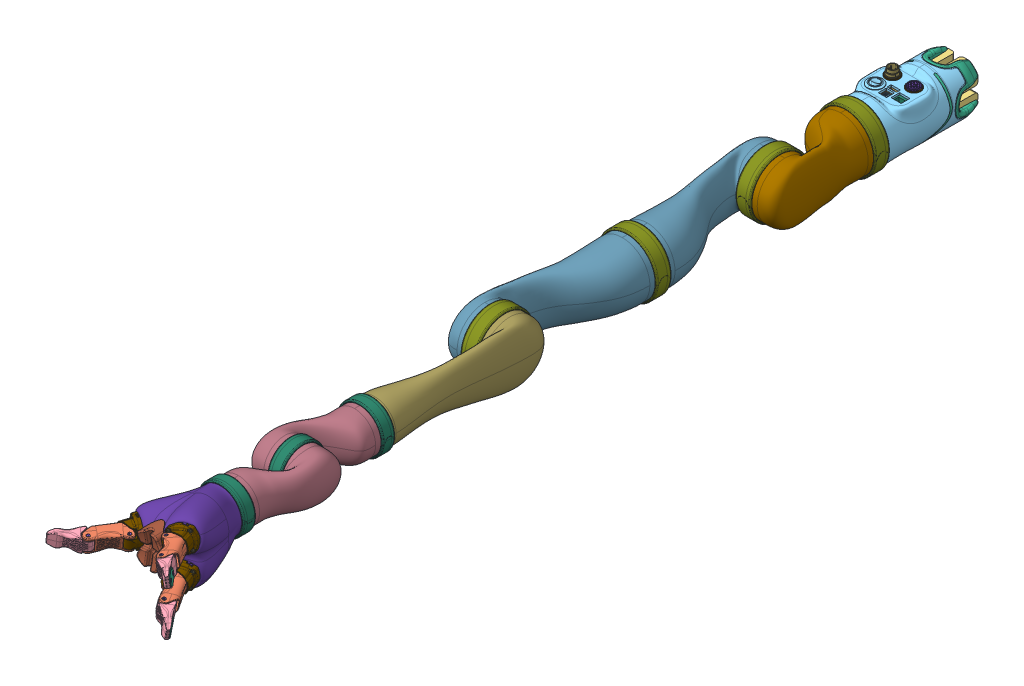
SolidWorks assembly JACO 7 DOF S + KG-3_revA.STEP, configuration 默认. Lengths in mm.
Overall size (206.48 115.63 1296.6).
225 component instances, 48 part files, 0 mates.
Components (placement in the parent):
- AP 4075 0003.STEP-1: AP 4075 0003.STEP [默认] at origin size (107.79 107.79 156.6)
  - AM 4075 0005.STEP-1: AM 4075 0005.STEP [默认] at origin size (107.79 107.79 156.6)
    - AM 4075 0004.STEP-1: AM 4075 0004.STEP [默认] at origin size (107.79 107.79 156.6)
      - AM 7525 0001.STEP-1: AM 7525 0001.STEP [默认] at (0 0 156.5) x (0 0 -1) z (0.382683 0.92388 0) size (25.6 82.5 82.5)
        - MR 7580 0001.STEP-1: MR 7580 0001.STEP [默认] at origin size (25.6 82.5 82.5)
        - MH 0304 0001.STEP-1: MH 0304 0001.STEP [默认] at (15 19.7505 29.5587) x (1 0 0) z (0 0.55557 0.83147) size (3 3 3.98)
      - MF 7549 0001_D_faut.STEP-1: MF 7549 0001_D_faut.STEP [默认] x (0 -1 0) z (-1 0 0) size (74.66 49 74.66)
      - MP 8010 0001_D_faut.STEP-1: MP 8010 0001_D_faut.STEP [默认] at (0 0 54) x (1 0 0) z (0 -1 0) size (77.22 9.56 77.22)
      - MT 8080 0008_D_faut.STEP-1: MT 8080 0008_D_faut.STEP [默认] at (0 0 58) x (0 -1 0) z (1 0 0) size (87.16 131.35 84.58)
    - DL 2311 0001_D_faut.STEP-1: DL 2311 0001_D_faut.STEP [默认] at (0 0 59.5) x (0 1 0) z (1 0 0) size (79.71 59.58 82.7)
  - AE 0000 0022_D_faut.STEP-1: AE 0000 0022_D_faut.STEP [默认] at (0.6864 -1.7716 54.8) x (0 -1 0) z (0 0 1) size (53.01 55.6 17.26)
    - PCB_Backplane_D_faut.STEP-1: PCB_Backplane_D_faut.STEP [默认] at (0.6913 -0.6913 -0.8) size (53.01 55.6 1.6)
    - HSEC8-125-01-X-DV-A_D_faut.STEP-1: HSEC8-125-01-X-DV-A_D_faut.STEP [默认] at (-5 0 0.8) x (0 -1 0) z (-1 0 0) size (27.8 9.3 7)
    - HSEC8-125-01-X-DV-A_D_faut.STEP-2: HSEC8-125-01-X-DV-A_D_faut.STEP [默认] at (5 0 0.8) x (0 -1 0) z (-1 0 0) size (27.8 9.3 7)
    - HSEC8-125-01-X-DV-A_D_faut.STEP-3: HSEC8-125-01-X-DV-A_D_faut.STEP [默认] at (15 0 0.8) x (0 -1 0) z (-1 0 0) size (27.8 9.3 7)
    - HSEC8-125-01-X-DV-A_D_faut.STEP-4: HSEC8-125-01-X-DV-A_D_faut.STEP [默认] at (-15 0 0.8) x (0 -1 0) z (-1 0 0) size (27.8 9.3 7)
    - Cap_Backplane_D_faut.STEP-1: Cap_Backplane_D_faut.STEP [默认] at (-29.1669 5.7481 0.8) x (1 0 0) z (0 -1 0) size (10 10.5 10)
    - Cap_Backplane_D_faut.STEP-2: Cap_Backplane_D_faut.STEP [默认] at (-29.1669 -5.4094 0.8) x (1 0 0) z (0 -1 0) size (10 10.5 10)
    - Cap_Backplane_D_faut.STEP-3: Cap_Backplane_D_faut.STEP [默认] at (-29.1669 -16.1366 0.8) x (1 0 0) z (0 -1 0) size (10 10.5 10)
    - Samtec-SIB-108-02-F-S_LEAD STYLE2PLATINGFPOSITIONS8ROWS.STEP-1: Samtec-SIB-108-02-F-S_LEAD STYLE2PLATINGFPOSITIONS8ROWS.STEP [默认] at (-4.2479 -0.6913 -0.8) x (0 -1 0) z (1 0 0) size (20.32 5.23 8.51)
    - Samtec-SIB-108-02-F-S_LEAD STYLE2PLATINGFPOSITIONS8ROWS.STEP-2: Samtec-SIB-108-02-F-S_LEAD STYLE2PLATINGFPOSITIONS8ROWS.STEP [默认] at (5.7521 -0.6913 -0.8) x (0 -1 0) z (1 0 0) size (20.32 5.23 8.51)
  - AE 0000 0021_D_faut.STEP-1: AE 0000 0021_D_faut.STEP [默认] at (-8.7893 14.275 82.5565) x (-1 0 0) z (0 -1 0) size (65 62 35.39)
    - EDAC-690-004-260-013_Default USB - Type A004-4 Contacts2-Gold Flash60-Vertical PCB0-Thermoplastic Black or Blue.STEP-1: EDAC-690-004-260-013_Default USB - Type A004-4 Contacts2-Gold Flash60-Vertical PCB0-Thermoplastic Black or Blue.STEP [默认] at (-10.8593 -15.6435 -15.675) x (-1 0 0) z (0 0 -1) size (15.84 7 18.8)
      - EDAC-690-004-260-013_690-004_690-004-260-013.STEP-1: EDAC-690-004-260-013_690-004_690-004-260-013.STEP [默认] at origin size (15.84 7 18.8)
        - EDAC-690-004-260-013_690-004_690-004-260-013-0.STEP-1: EDAC-690-004-260-013_690-004_690-004-260-013-0.STEP [默认] at origin size (15.84 7 18.8)
    - Lumberg_0315_04_D_faut.STEP-1: Lumberg_0315_04_D_faut.STEP [默认] at (7.2107 0.5565 -31.805) x (0 0 1) z (1 0 0) size (18 20 20)
      - 0315_04_D_faut.STEP-1: 0315_04_D_faut.STEP [默认] at (24.0344 -13.1103 0) x (0 1 0) z (0 0 1) size (20 18 20)
    - PCB_Mezzanine_2_D_faut.STEP-1: PCB_Mezzanine_2_D_faut.STEP [默认] at (-41.4793 -37.2935 0) size (65 62 1.55)
    - c-5787834-1-a-3d_D_faut.STEP-1: c-5787834-1-a-3d_D_faut.STEP [默认] at (-10.8263 -26.7115 -16.075) x (1 0 0) z (0 0 -1) size (15.15 11.46 19.64)
    - SI-46001-F_D_faut.STEP-1: SI-46001-F_D_faut.STEP [默认] at (-19.9593 -12.9235 -17.795) x (-1 0 0) z (0 1 0) size (16.26 17.02 17.02)
    - Main_Switch_D_faut.STEP-1: Main_Switch_D_faut.STEP [默认] at (9.0907 -23.4405 -4.815) x (0 1 0) z (0 0 1) size (23 23 28.61)
    - 0305_08-1_D_faut.STEP-1: 0305_08-1_D_faut.STEP [默认] at (-12.2893 0.5565 -31.705) x (-1 0 0) z (0 0 -1) size (20 20 18.1)
    - Lumberg_Screw_D_faut.STEP-1: Lumberg_Screw_D_faut.STEP [默认] at (-24.7893 0.5565 -22.305) x (0.150539 0.988604 0) z (0 0 1) size (20 20 3)
    - Lumberg_Screw_D_faut.STEP-2: Lumberg_Screw_D_faut.STEP [默认] at (7.2107 0.5565 -22.305) x (0.972925 0.231122 0) z (0 0 1) size (20 20 3)
  - MF 7482 0001_D_faut.STEP-1: MF 7482 0001_D_faut.STEP [默认] at (0 0 119.85) x (0 1 0) z (0 0 -1) size (50.6 74.1 81.85)
  - MH 0306 0003_96817A310.STEP-1: MH 0306 0003_96817A310.STEP [默认] at (20 -11.42 55.6) x (0.976803 -0.214141 0) z (0 0 1) size (5 5 8.1)
  - MH 0306 0003_96817A310.STEP-2: MH 0306 0003_96817A310.STEP [默认] at (-17 -24.5 56.5) x (-0.999847 0.017484 0) z (0 0 1) size (5 5 8.1)
  - MH 0306 0003_96817A310.STEP-3: MH 0306 0003_96817A310.STEP [默认] at (17 -24.5 56.5) x (0.590726 0.806872 0) z (0 0 1) size (5 5 8.1)
  - MH 0306 0003_96817A310.STEP-4: MH 0306 0003_96817A310.STEP [默认] at (-20 -11.42 55.6) x (0.99968 -0.025284 0) z (0 0 1) size (5 5 8.1)
  - MF 1064 0002_D_faut.STEP-1: MF 1064 0002_D_faut.STEP [默认] at (-0.0013 32 108.003) x (-1 0 0) z (0 -1 0) size (64 31 8.22)
  - MF 1064 0002_D_faut.STEP-2: MF 1064 0002_D_faut.STEP [默认] at (-0.0013 23.775 108.003) x (-1 0 0) z (0 -1 0) size (64 31 8.22)
  - MP 6856 0001_D_faut.STEP-1: MP 6856 0001_D_faut.STEP [默认] at (33.94 -0.2666 113.85) x (-1 0 0) z (0 0 1) size (67.5 5.5 56)
  - CS 0000 0003_D_faut.STEP-1: CS 0000 0003_D_faut.STEP [默认] at (-17.88 20.5 106) x (0.009293 0 -0.999957) z (0 -1 0) size (23 23 28.61)
  - MI 8660 0001_D_faut.STEP-1: MI 8660 0001_D_faut.STEP [默认] x (0 -1 0) z (-1 0 0) size (82.51 46.49 82.53)
  - AE 0000 0023_D_faut.STEP-1: AE 0000 0023_D_faut.STEP [默认] at (32.69 3.0084 116.85) x (-1 0 0) z (0 -1 0) size (65 59 1.55)
  - MH 0305 0003_92005A114.STEP-1: MH 0305 0003_92005A114.STEP [默认] at (-28.31 -1.2166 68.19) x (1 0 0) z (0 1 0) size (6 6 7.42)
  - MH 0305 0003_92005A114.STEP-2: MH 0305 0003_92005A114.STEP [默认] at (28.69 -1.2166 68.19) x (1 0 0) z (0 1 0) size (6 6 7.42)
- AM 7575 0005.STEP-1: AM 7575 0005.STEP [默认] at (0 0 157) x (0 0 1) z (-1 0 0) size (172.49 107.79 107.79)
  - AM 7575 0002_D_faut.STEP-1: AM 7575 0002_D_faut.STEP [默认] at origin size (172.49 107.79 107.79)
    - AM 7525 0001.STEP-1: AM 7525 0001.STEP [默认] x (1 0 0) z (0 -0.382683 0.92388) size (25.6 82.5 82.5)
      - MR 7580 0001.STEP-1: MR 7580 0001.STEP [默认] at origin size (25.6 82.5 82.5)
      - MH 0304 0001.STEP-1: MH 0304 0001.STEP [默认] at (15 19.7505 29.5587) x (1 0 0) z (0 0.55557 0.83147) size (3 3 3.98)
    - AM 7525 0001.STEP-2: AM 7525 0001.STEP [默认] at (118.5 0 1.5) x (0 0 -1) z (0.92388 -0.382683 0) size (25.6 82.5 82.5)
      - MR 7580 0001.STEP-1: MR 7580 0001.STEP [默认] at origin size (25.6 82.5 82.5)
      - MH 0304 0001.STEP-1: MH 0304 0001.STEP [默认] at (15 19.7505 29.5587) x (1 0 0) z (0 0.55557 0.83147) size (3 3 3.98)
    - MT 8080 0001_D_faut.STEP-1: MT 8080 0001_D_faut.STEP [默认] at (118.5 0 -7) x (-1 0 0) z (0 1 0) size (151.26 82.78 82.54)
- AM 7558 0003.STEP-1: AM 7558 0003.STEP [默认] at (-1.5 0 685.5) x (1 0 0) z (0 0 -1) size (63.12 107.79 260.9)
  - AM 7558 0001_D_faut.STEP-1: AM 7558 0001_D_faut.STEP [默认] at origin size (63.12 107.79 260.9)
    - AM 7525 0001.STEP-1: AM 7525 0001.STEP [默认] x (1 0 0) z (0 -0.382683 0.92388) size (25.6 82.5 82.5)
      - MR 7580 0001.STEP-1: MR 7580 0001.STEP [默认] at origin size (25.6 82.5 82.5)
      - MH 0304 0001.STEP-1: MH 0304 0001.STEP [默认] at (15 19.7505 29.5587) x (1 0 0) z (0 0.55557 0.83147) size (3 3 3.98)
    - AM 5818 0003.STEP-1: AM 5818 0003.STEP [默认] at (11.25 0 -207) x (0 0 1) z (1 0 0) size (18 63 63)
      - MR 5862 0001.STEP-1: MR 5862 0001.STEP [默认] at origin size (18 63 63)
      - MH 0303 0003_D_faut.STEP-1: MH 0303 0003_D_faut.STEP [默认] at (11 -14.9 -25.8076) x (0 0.5 0.866025) z (-0.866025 -0.433013 0.25) size (2.5 3 3)
    - MT 8062 0001_D_faut.STEP-1: MT 8062 0001_D_faut.STEP [默认] at (8.5 0 0) x (0 0 -1) z (-1 0 0) size (241.26 82.53 63.12)
- KR823.STEP-1: KR823.STEP [默认] at (9.75 0 900) x (0 0 1) z (0 1 0) size (135.27 79.25 63.1)
  - AM 5858 0008.STEP-1: AM 5858 0008.STEP [默认] at origin size (135.27 79.25 63.1)
    - AM 5818 0003.STEP-1: AM 5818 0003.STEP [默认] at (-7 0 0) x (1 0 0) z (0 -1 0) size (18 63 63)
      - MR 5862 0001.STEP-1: MR 5862 0001.STEP [默认] at origin size (18 63 63)
      - MH 0303 0003_D_faut.STEP-1: MH 0303 0003_D_faut.STEP [默认] at (11 -14.9 -25.8076) x (0 0.5 0.866025) z (-0.866025 -0.433013 0.25) size (2.5 3 3)
    - AM 5818 0003.STEP-2: AM 5818 0003.STEP [默认] at (96.5 -0.25 0) x (0 -1 0) z (-1 0 0) size (18 63 63)
      - MR 5862 0001.STEP-1: MR 5862 0001.STEP [默认] at origin size (18 63 63)
      - MH 0303 0003_D_faut.STEP-1: MH 0303 0003_D_faut.STEP [默认] at (11 -14.9 -25.8076) x (0 0.5 0.866025) z (-0.866025 -0.433013 0.25) size (2.5 3 3)
    - MT 6262 0006.STEP-1: MT 6262 0006.STEP [默认] x (-1 0 0) z (0 0 1) size (128.27 79.25 63.1)
- KR823.STEP-2: KR823.STEP [默认] at (9.75 0 1093) x (0 0 -1) z (0 1 0) size (135.27 79.25 63.1)
  - AM 5858 0008.STEP-1: AM 5858 0008.STEP [默认] at origin size (135.27 79.25 63.1)
    - AM 5818 0003.STEP-1: AM 5818 0003.STEP [默认] at (-7 0 0) x (1 0 0) z (0 -1 0) size (18 63 63)
      - MR 5862 0001.STEP-1: MR 5862 0001.STEP [默认] at origin size (18 63 63)
      - MH 0303 0003_D_faut.STEP-1: MH 0303 0003_D_faut.STEP [默认] at (11 -14.9 -25.8076) x (0 0.5 0.866025) z (-0.866025 -0.433013 0.25) size (2.5 3 3)
    - AM 5818 0003.STEP-2: AM 5818 0003.STEP [默认] at (96.5 -0.25 0) x (0 -1 0) z (-1 0 0) size (18 63 63)
      - MR 5862 0001.STEP-1: MR 5862 0001.STEP [默认] at origin size (18 63 63)
      - MH 0303 0003_D_faut.STEP-1: MH 0303 0003_D_faut.STEP [默认] at (11 -14.9 -25.8076) x (0 0.5 0.866025) z (-0.866025 -0.433013 0.25) size (2.5 3 3)
    - MT 6262 0006.STEP-1: MT 6262 0006.STEP [默认] x (-1 0 0) z (0 0 1) size (128.27 79.25 63.1)
- KR822.STEP-1: KR822.STEP [默认] at (-10.5 0 275.5) x (0 0 1) z (0 1 0) size (258.74 107.79 107.79)
  - AM 7575 0010.STEP-1: AM 7575 0010.STEP [默认] at origin size (258.74 107.79 107.79)
    - AM 7525 0001.STEP-1: AM 7525 0001.STEP [默认] at (0 8.5 0) x (0 -1 0) z (-0.92388 0 -0.382683) size (25.6 82.5 82.5)
      - MR 7580 0001.STEP-1: MR 7580 0001.STEP [默认] at origin size (25.6 82.5 82.5)
      - MH 0304 0001.STEP-1: MH 0304 0001.STEP [默认] at (15 19.7505 29.5587) x (1 0 0) z (0 0.55557 0.83147) size (3 3 3.98)
    - AM 7525 0001.STEP-2: AM 7525 0001.STEP [默认] at (204.75 8.75 0) x (-1 0 0) z (0 0.92388 -0.382683) size (25.6 82.5 82.5)
      - MR 7580 0001.STEP-1: MR 7580 0001.STEP [默认] at origin size (25.6 82.5 82.5)
      - MH 0304 0001.STEP-1: MH 0304 0001.STEP [默认] at (15 19.7505 29.5587) x (1 0 0) z (0 0.55557 0.83147) size (3 3 3.98)
    - MT 8080 0009_D_faut.STEP-1: MT 8080 0009_D_faut.STEP [默认] at origin size (237.61 85.04 82.69)
- KR822.STEP-2: KR822.STEP [默认] at (-10.5 0 685.5) x (0 0 -1) z (0 -1 0) size (258.74 107.79 107.79)
  - AM 7575 0010.STEP-1: AM 7575 0010.STEP [默认] at origin size (258.74 107.79 107.79)
    - AM 7525 0001.STEP-1: AM 7525 0001.STEP [默认] at (0 8.5 0) x (0 -1 0) z (-0.92388 0 -0.382683) size (25.6 82.5 82.5)
      - MR 7580 0001.STEP-1: MR 7580 0001.STEP [默认] at origin size (25.6 82.5 82.5)
      - MH 0304 0001.STEP-1: MH 0304 0001.STEP [默认] at (15 19.7505 29.5587) x (1 0 0) z (0 0.55557 0.83147) size (3 3 3.98)
    - AM 7525 0001.STEP-2: AM 7525 0001.STEP [默认] at (204.75 8.75 0) x (-1 0 0) z (0 0.92388 -0.382683) size (25.6 82.5 82.5)
      - MR 7580 0001.STEP-1: MR 7580 0001.STEP [默认] at origin size (25.6 82.5 82.5)
      - MH 0304 0001.STEP-1: MH 0304 0001.STEP [默认] at (15 19.7505 29.5587) x (1 0 0) z (0 0.55557 0.83147) size (3 3 3.98)
    - MT 8080 0009_D_faut.STEP-1: MT 8080 0009_D_faut.STEP [默认] at origin size (237.61 85.04 82.69)
- AM 5864 0001.STEP-1: AM 5864 0001.STEP [默认] at (6 0 996.5) x (0 0 1) z (1 0 0) size (69.01 69 19.58)
  - MI 5864 0001_D_faut.STEP-1: MI 5864 0001_D_faut.STEP [默认] at origin size (69.01 39.42 19.58)
  - MI 5864 0001_D_faut.STEP-2: MI 5864 0001_D_faut.STEP [默认] x (-1 0 0) z (0 0 1) size (69.01 39.42 19.58)
- AM 5864 0001.STEP-2: AM 5864 0001.STEP [默认] at (9.75 0 889) size (69.01 69 19.58)
  - MI 5864 0001_D_faut.STEP-1: MI 5864 0001_D_faut.STEP [默认] at origin size (69.01 39.42 19.58)
  - MI 5864 0001_D_faut.STEP-2: MI 5864 0001_D_faut.STEP [默认] x (-1 0 0) z (0 0 1) size (69.01 39.42 19.58)
- AM 7584 0001.STEP-1: AM 7584 0001.STEP [默认] at (-6.25 0 685.5) x (0 -0.382683 -0.92388) z (1 0 0) size (88.5 88.5 23.11)
  - MI 7584 0001_D_faut.STEP-1: MI 7584 0001_D_faut.STEP [默认] at origin size (86.29 65.12 23.11)
  - MI 7584 0001_D_faut.STEP-2: MI 7584 0001_D_faut.STEP [默认] x (-1 0 0) z (0 0 1) size (86.29 65.12 23.11)
- AM 7584 0001.STEP-2: AM 7584 0001.STEP [默认] at (2.75 0 275.5) x (0 -0.382683 0.92388) z (-1 0 0) size (88.5 88.5 23.11)
  - MI 7584 0001_D_faut.STEP-1: MI 7584 0001_D_faut.STEP [默认] at origin size (86.29 65.12 23.11)
  - MI 7584 0001_D_faut.STEP-2: MI 7584 0001_D_faut.STEP [默认] x (-1 0 0) z (0 0 1) size (86.29 65.12 23.11)
- AM 7584 0001.STEP-3: AM 7584 0001.STEP [默认] at (0 0 152.25) x (0.92388 -0.382683 0) z (0 0 1) size (88.5 88.5 23.11)
  - MI 7584 0001_D_faut.STEP-1: MI 7584 0001_D_faut.STEP [默认] at origin size (86.29 65.12 23.11)
  - MI 7584 0001_D_faut.STEP-2: MI 7584 0001_D_faut.STEP [默认] x (-1 0 0) z (0 0 1) size (86.29 65.12 23.11)
- AM 7584 0001.STEP-4: AM 7584 0001.STEP [默认] at (-1.75 0 476) x (-0.92388 0.382683 0) z (0 0 1) size (88.5 88.5 23.11)
  - MI 7584 0001_D_faut.STEP-1: MI 7584 0001_D_faut.STEP [默认] at origin size (86.29 65.12 23.11)
  - MI 7584 0001_D_faut.STEP-2: MI 7584 0001_D_faut.STEP [默认] x (-1 0 0) z (0 0 1) size (86.29 65.12 23.11)
- AM 5864 0001.STEP-3: AM 5864 0001.STEP [默认] at (9.75 0 1104) x (-1 0 0) z (0 0 -1) size (69.01 69 19.58)
  - MI 5864 0001_D_faut.STEP-1: MI 5864 0001_D_faut.STEP [默认] at origin size (69.01 39.42 19.58)
  - MI 5864 0001_D_faut.STEP-2: MI 5864 0001_D_faut.STEP [默认] x (-1 0 0) z (0 0 1) size (69.01 39.42 19.58)
- AM 0058 0006.STEP-1: AM 0058 0006.STEP [默认] at (9.75 0 1100.5) x (1 0 0) z (0 -1 0) size (117.07 110.65 99.5)
  - AM 0058 0005.STEP-1: AM 0058 0005.STEP [默认] at (-0.2165 7 -0.125) size (117.07 110.65 99.5)
    - AM 5818 0003.STEP-1: AM 5818 0003.STEP [默认] at (0.2165 -7 0.125) x (0 1 0) z (-1 0 0) size (18 63 63)
      - MR 5862 0001.STEP-1: MR 5862 0001.STEP [默认] at origin size (18 63 63)
      - MH 0303 0003_D_faut.STEP-1: MH 0303 0003_D_faut.STEP [默认] at (11 -14.9 -25.8076) x (0 0.5 0.866025) z (-0.866025 -0.433013 0.25) size (2.5 3 3)
    - MT 0062 0003_D_faut.STEP-1: MT 0062 0003_D_faut.STEP [默认] at (0.2165 88 0.125) size (117.07 103.65 99.5)
- AM 3240 0004_D_faut.STEP-1: AM 3240 0004_D_faut.STEP [默认] at (-22.6098 0.2289 1189.5785) x (0.922476 -0.196878 0.33208) z (0.345056 0.034715 -0.93794) size (55.21 37.09 114.41)
  - MI 3636 0001.STEP-1: MI 3636 0001.STEP [默认] at (0 0 -13.5762) x (0 0 1) z (0 1 0) size (37.04 38.09 37.09)
    - MI 3636 0001_D_faut.STEP-1: MI 3636 0001_D_faut.STEP [默认] at origin size (37.04 38.09 37.09)
    - MB 0309 0002_D_faut.STEP-1: MB 0309 0002_D_faut.STEP [默认] at (-10 10.5 0) x (0 0 1) z (-0.866025 -0.5 0) size (15 9 9)
  - MI 2256 0001.STEP-1: MI 2256 0001.STEP [默认] at (5.1527 0 -24.2139) x (-0.258819 0 -0.965926) z (0 -1 0) size (57.72 28.65 24.82)
    - MI 2256 0001_D_faut.STEP-1: MI 2256 0001_D_faut.STEP [默认] at origin size (57.72 28.12 24.82)
    - MB 0309 0001_D_faut.STEP-1: MB 0309 0001_D_faut.STEP [默认] at (-2 5 -9.5) x (0 0 1) z (-0.945183 0.326541 0) size (3.5 9 9)
    - MB 0309 0001_D_faut.STEP-2: MB 0309 0001_D_faut.STEP [默认] at (-2 5 9.5) x (0 0 1) z (-0.945183 0.326541 0) size (3.5 9 9)
    - MB 0309 0001_D_faut.STEP-3: MB 0309 0001_D_faut.STEP [默认] at (42 2 -9.5) x (0 0 1) z (0.63012 0.776498 0) size (3.5 9 9)
    - MB 0309 0001_D_faut.STEP-4: MB 0309 0001_D_faut.STEP [默认] at (42 2 9.5) x (0 0 1) z (0.63012 0.776498 0) size (3.5 9 9)
  - MI 2253 0001.STEP-1: MI 2253 0001.STEP [默认] at (-3.7858 0 -65.3004) x (-0.422618 0 -0.906308) z (0 -1 0) size (53.07 21.6 24.35)
    - MI 2253 0001_molded_version.STEP-1: MI 2253 0001_molded_version.STEP [默认] at origin size (53.07 21.6 24.35)
    - MB 0309 0002_D_faut.STEP-1: MB 0309 0002_D_faut.STEP [默认] x (0 0 -1) z (-1 0 0) size (15 9 9)
    - MB 0208 0001_D_faut.STEP-1: MB 0208 0001_D_faut.STEP [默认] at (23.2436 -8.7828 0) x (0.121869 -0.992546 0) z (0 0 1) size (2.5 8 8)
    - MB 0208 0001_D_faut.STEP-2: MB 0208 0001_D_faut.STEP [默认] at (38.1318 -6.9547 0) x (0.121869 -0.992546 0) z (0.166838 0.020485 0.985771) size (2.5 8 8)
  - MI 1502 0001_D_faut.STEP-1: MI 1502 0001_D_faut.STEP [默认] at (-21.2126 0 -77.513) x (0 1 0) z (-0.951057 0 0.309017) size (19.37 25 1.54)
  - MH 0205 0003_D_faut.STEP-1: MH 0205 0003_D_faut.STEP [默认] at (-23.7563 0 -81.9438) x (-0.309017 0.000713 -0.951056) z (0.951057 0 -0.309017) size (5 5 0.3)
  - MH 0205 0003_D_faut.STEP-2: MH 0205 0003_D_faut.STEP [默认] at (-28.3916 0 -96.2096) x (-0.309017 0.000713 -0.951056) z (0.951057 0 -0.309017) size (5 5 0.3)
  - MH 0204 0004_D_faut.STEP-1: MH 0204 0004_D_faut.STEP [默认] at (-19.9521 0 -83.1799) x (-0.039565 0.991769 -0.12177) z (0.306474 0.128036 0.943229) size (4 4.3 4)
  - MH 0204 0004_D_faut.STEP-2: MH 0204 0004_D_faut.STEP [默认] at (-24.5874 0 -97.4457) x (0.295789 0.289446 0.910346) z (0.089444 -0.957194 0.27528) size (4 4.3 4)
  - MA 0323 0001_D_faut.STEP-1: MA 0323 0001_D_faut.STEP [默认] at (-3.7858 0 -65.3004) x (0 1 0) z (1 0 0) size (22.7 3 3)
  - MA 0323 0001_D_faut.STEP-2: MA 0323 0001_D_faut.STEP [默认] at (10.5 0 -23.5762) x (0 1 0) z (1 0 0) size (22.7 3 3)
  - MH 0204 0004_D_faut.STEP-3: MH 0204 0004_D_faut.STEP [默认] at (-3.7858 -7.35 -65.3004) x (-0.96685 0 -0.255343) z (-0.255343 0 0.96685) size (4 4.3 4)
  - MH 0204 0004_D_faut.STEP-4: MH 0204 0004_D_faut.STEP [默认] at (10.5 -7.35 -23.5762) x (-0.96685 0 -0.255343) z (-0.255343 0 0.96685) size (4 4.3 4)
  - MH 0204 0004_D_faut.STEP-5: MH 0204 0004_D_faut.STEP [默认] at (-3.7858 7.35 -65.3004) size (4 4.3 4)
  - MH 0204 0004_D_faut.STEP-6: MH 0204 0004_D_faut.STEP [默认] at (10.5 7.35 -23.5762) size (4 4.3 4)
- AM 3240 0004_D_faut.STEP-2: AM 3240 0004_D_faut.STEP [默认] at (38.0215 22.5697 1189.6482) x (-0.923011 -0.176281 0.342017) z (-0.336327 -0.062156 -0.939692) size (55.21 37.09 114.41)
  - MI 3636 0001.STEP-1: MI 3636 0001.STEP [默认] at (0 0 -13.5762) x (0 0 1) z (0 1 0) size (37.04 38.09 37.09)
    - MI 3636 0001_D_faut.STEP-1: MI 3636 0001_D_faut.STEP [默认] at origin size (37.04 38.09 37.09)
    - MB 0309 0002_D_faut.STEP-1: MB 0309 0002_D_faut.STEP [默认] at (-10 10.5 0) x (0 0 1) z (-0.866025 -0.5 0) size (15 9 9)
  - MI 2256 0001.STEP-1: MI 2256 0001.STEP [默认] at (5.1527 0 -24.2139) x (-0.258819 0 -0.965926) z (0 -1 0) size (57.72 28.65 24.82)
    - MI 2256 0001_D_faut.STEP-1: MI 2256 0001_D_faut.STEP [默认] at origin size (57.72 28.12 24.82)
    - MB 0309 0001_D_faut.STEP-1: MB 0309 0001_D_faut.STEP [默认] at (-2 5 -9.5) x (0 0 1) z (-0.945183 0.326541 0) size (3.5 9 9)
    - MB 0309 0001_D_faut.STEP-2: MB 0309 0001_D_faut.STEP [默认] at (-2 5 9.5) x (0 0 1) z (-0.945183 0.326541 0) size (3.5 9 9)
    - MB 0309 0001_D_faut.STEP-3: MB 0309 0001_D_faut.STEP [默认] at (42 2 -9.5) x (0 0 1) z (0.63012 0.776498 0) size (3.5 9 9)
    - MB 0309 0001_D_faut.STEP-4: MB 0309 0001_D_faut.STEP [默认] at (42 2 9.5) x (0 0 1) z (0.63012 0.776498 0) size (3.5 9 9)
  - MI 2253 0001.STEP-1: MI 2253 0001.STEP [默认] at (-3.7858 0 -65.3004) x (-0.422618 0 -0.906308) z (0 -1 0) size (53.07 21.6 24.35)
    - MI 2253 0001_molded_version.STEP-1: MI 2253 0001_molded_version.STEP [默认] at origin size (53.07 21.6 24.35)
    - MB 0309 0002_D_faut.STEP-1: MB 0309 0002_D_faut.STEP [默认] x (0 0 -1) z (-1 0 0) size (15 9 9)
    - MB 0208 0001_D_faut.STEP-1: MB 0208 0001_D_faut.STEP [默认] at (23.2436 -8.7828 0) x (0.121869 -0.992546 0) z (0 0 1) size (2.5 8 8)
    - MB 0208 0001_D_faut.STEP-2: MB 0208 0001_D_faut.STEP [默认] at (38.1318 -6.9547 0) x (0.121869 -0.992546 0) z (0.166838 0.020485 0.985771) size (2.5 8 8)
  - MI 1502 0001_D_faut.STEP-1: MI 1502 0001_D_faut.STEP [默认] at (-21.2126 0 -77.513) x (0 1 0) z (-0.951057 0 0.309017) size (19.37 25 1.54)
  - MH 0205 0003_D_faut.STEP-1: MH 0205 0003_D_faut.STEP [默认] at (-23.7563 0 -81.9438) x (-0.309017 0.000713 -0.951056) z (0.951057 0 -0.309017) size (5 5 0.3)
  - MH 0205 0003_D_faut.STEP-2: MH 0205 0003_D_faut.STEP [默认] at (-28.3916 0 -96.2096) x (-0.309017 0.000713 -0.951056) z (0.951057 0 -0.309017) size (5 5 0.3)
  - MH 0204 0004_D_faut.STEP-1: MH 0204 0004_D_faut.STEP [默认] at (-19.9521 0 -83.1799) x (-0.039565 0.991769 -0.12177) z (0.306474 0.128036 0.943229) size (4 4.3 4)
  - MH 0204 0004_D_faut.STEP-2: MH 0204 0004_D_faut.STEP [默认] at (-24.5874 0 -97.4457) x (0.295789 0.289446 0.910346) z (0.089444 -0.957194 0.27528) size (4 4.3 4)
  - MA 0323 0001_D_faut.STEP-1: MA 0323 0001_D_faut.STEP [默认] at (-3.7858 0 -65.3004) x (0 1 0) z (1 0 0) size (22.7 3 3)
  - MA 0323 0001_D_faut.STEP-2: MA 0323 0001_D_faut.STEP [默认] at (10.5 0 -23.5762) x (0 1 0) z (1 0 0) size (22.7 3 3)
  - MH 0204 0004_D_faut.STEP-3: MH 0204 0004_D_faut.STEP [默认] at (-3.7858 -7.35 -65.3004) x (-0.96685 0 -0.255343) z (-0.255343 0 0.96685) size (4 4.3 4)
  - MH 0204 0004_D_faut.STEP-4: MH 0204 0004_D_faut.STEP [默认] at (10.5 -7.35 -23.5762) x (-0.96685 0 -0.255343) z (-0.255343 0 0.96685) size (4 4.3 4)
  - MH 0204 0004_D_faut.STEP-5: MH 0204 0004_D_faut.STEP [默认] at (-3.7858 7.35 -65.3004) size (4 4.3 4)
  - MH 0204 0004_D_faut.STEP-6: MH 0204 0004_D_faut.STEP [默认] at (10.5 7.35 -23.5762) size (4 4.3 4)
- AM 3240 0004_D_faut.STEP-3: AM 3240 0004_D_faut.STEP [默认] at (38.0266 -22.5431 1189.6481) x (-0.923363 0.174422 0.342019) z (-0.336265 0.062483 -0.939692) size (55.21 37.09 114.41)
  - MI 3636 0001.STEP-1: MI 3636 0001.STEP [默认] at (0 0 -13.5762) x (0 0 1) z (0 1 0) size (37.04 38.09 37.09)
    - MI 3636 0001_D_faut.STEP-1: MI 3636 0001_D_faut.STEP [默认] at origin size (37.04 38.09 37.09)
    - MB 0309 0002_D_faut.STEP-1: MB 0309 0002_D_faut.STEP [默认] at (-10 10.5 0) x (0 0 1) z (-0.866025 -0.5 0) size (15 9 9)
  - MI 2256 0001.STEP-1: MI 2256 0001.STEP [默认] at (5.1527 0 -24.2139) x (-0.258819 0 -0.965926) z (0 -1 0) size (57.72 28.65 24.82)
    - MI 2256 0001_D_faut.STEP-1: MI 2256 0001_D_faut.STEP [默认] at origin size (57.72 28.12 24.82)
    - MB 0309 0001_D_faut.STEP-1: MB 0309 0001_D_faut.STEP [默认] at (-2 5 -9.5) x (0 0 1) z (-0.945183 0.326541 0) size (3.5 9 9)
    - MB 0309 0001_D_faut.STEP-2: MB 0309 0001_D_faut.STEP [默认] at (-2 5 9.5) x (0 0 1) z (-0.945183 0.326541 0) size (3.5 9 9)
    - MB 0309 0001_D_faut.STEP-3: MB 0309 0001_D_faut.STEP [默认] at (42 2 -9.5) x (0 0 1) z (0.63012 0.776498 0) size (3.5 9 9)
    - MB 0309 0001_D_faut.STEP-4: MB 0309 0001_D_faut.STEP [默认] at (42 2 9.5) x (0 0 1) z (0.63012 0.776498 0) size (3.5 9 9)
  - MI 2253 0001.STEP-1: MI 2253 0001.STEP [默认] at (-3.7858 0 -65.3004) x (-0.422618 0 -0.906308) z (0 -1 0) size (53.07 21.6 24.35)
    - MI 2253 0001_molded_version.STEP-1: MI 2253 0001_molded_version.STEP [默认] at origin size (53.07 21.6 24.35)
    - MB 0309 0002_D_faut.STEP-1: MB 0309 0002_D_faut.STEP [默认] x (0 0 -1) z (-1 0 0) size (15 9 9)
    - MB 0208 0001_D_faut.STEP-1: MB 0208 0001_D_faut.STEP [默认] at (23.2436 -8.7828 0) x (0.121869 -0.992546 0) z (0 0 1) size (2.5 8 8)
    - MB 0208 0001_D_faut.STEP-2: MB 0208 0001_D_faut.STEP [默认] at (38.1318 -6.9547 0) x (0.121869 -0.992546 0) z (0.166838 0.020485 0.985771) size (2.5 8 8)
  - MI 1502 0001_D_faut.STEP-1: MI 1502 0001_D_faut.STEP [默认] at (-21.2126 0 -77.513) x (0 1 0) z (-0.951057 0 0.309017) size (19.37 25 1.54)
  - MH 0205 0003_D_faut.STEP-1: MH 0205 0003_D_faut.STEP [默认] at (-23.7563 0 -81.9438) x (-0.309017 0.000713 -0.951056) z (0.951057 0 -0.309017) size (5 5 0.3)
  - MH 0205 0003_D_faut.STEP-2: MH 0205 0003_D_faut.STEP [默认] at (-28.3916 0 -96.2096) x (-0.309017 0.000713 -0.951056) z (0.951057 0 -0.309017) size (5 5 0.3)
  - MH 0204 0004_D_faut.STEP-1: MH 0204 0004_D_faut.STEP [默认] at (-19.9521 0 -83.1799) x (-0.039565 0.991769 -0.12177) z (0.306474 0.128036 0.943229) size (4 4.3 4)
  - MH 0204 0004_D_faut.STEP-2: MH 0204 0004_D_faut.STEP [默认] at (-24.5874 0 -97.4457) x (0.295789 0.289446 0.910346) z (0.089444 -0.957194 0.27528) size (4 4.3 4)
  - MA 0323 0001_D_faut.STEP-1: MA 0323 0001_D_faut.STEP [默认] at (-3.7858 0 -65.3004) x (0 1 0) z (1 0 0) size (22.7 3 3)
  - MA 0323 0001_D_faut.STEP-2: MA 0323 0001_D_faut.STEP [默认] at (10.5 0 -23.5762) x (0 1 0) z (1 0 0) size (22.7 3 3)
  - MH 0204 0004_D_faut.STEP-3: MH 0204 0004_D_faut.STEP [默认] at (-3.7858 -7.35 -65.3004) x (-0.96685 0 -0.255343) z (-0.255343 0 0.96685) size (4 4.3 4)
  - MH 0204 0004_D_faut.STEP-4: MH 0204 0004_D_faut.STEP [默认] at (10.5 -7.35 -23.5762) x (-0.96685 0 -0.255343) z (-0.255343 0 0.96685) size (4 4.3 4)
  - MH 0204 0004_D_faut.STEP-5: MH 0204 0004_D_faut.STEP [默认] at (-3.7858 7.35 -65.3004) size (4 4.3 4)
  - MH 0204 0004_D_faut.STEP-6: MH 0204 0004_D_faut.STEP [默认] at (10.5 7.35 -23.5762) size (4 4.3 4)
- MH 0306 0001_92125A126.STEP-1: MH 0306 0001_92125A126.STEP [默认] at (9.75 31.5 1096.5) x (0.536869 0 0.843666) z (0 1 0) size (6 6 6.14)
- MH 0306 0001_92125A126.STEP-2: MH 0306 0001_92125A126.STEP [默认] at (-17.5298 15.75 1096.5) x (0.268435 0.464942 0.843666) z (-0.866025 0.5 0) size (6 6 6.14)
- MH 0306 0001_92125A126.STEP-3: MH 0306 0001_92125A126.STEP [默认] at (-17.5298 -15.75 1096.5) x (-0.268435 0.464942 0.843666) z (-0.866025 -0.5 0) size (6 6 6.14)
- MH 0306 0001_92125A126.STEP-4: MH 0306 0001_92125A126.STEP [默认] at (9.75 -31.5 1096.5) x (-0.536869 0 0.843666) z (0 -1 0) size (6 6 6.14)
- MH 0306 0001_92125A126.STEP-5: MH 0306 0001_92125A126.STEP [默认] at (37.0298 -15.75 1096.5) x (-0.268435 -0.464942 0.843666) z (0.866025 -0.5 0) size (6 6 6.14)
- MH 0306 0001_92125A126.STEP-6: MH 0306 0001_92125A126.STEP [默认] at (37.0298 15.75 1096.5) x (0.268435 -0.464942 0.843666) z (0.866025 0.5 0) size (6 6 6.14)
- MO 0000 0012_D_faut.STEP-1: MO 0000 0012_D_faut.STEP [默认] at (9.75 0 1195.4909) x (1 0 0) z (0 -1 0) size (46.1 30.57 60.17)
- MH 2510 0001_91292A014.STEP-1: MH 2510 0001_91292A014.STEP [默认] at (46.193 -35.9607 1184.4249) x (-0.093664 0.990631 0.099388) z (-0.336265 0.062483 -0.939692) size (4.5 4.5 12.62)
- MH 2510 0001_91292A014.STEP-2: MH 2510 0001_91292A014.STEP [默认] at (26.0087 -32.1437 1196.2118) x (-0.198931 0.97057 0.135723) z (-0.336265 0.062483 -0.939692) size (4.5 4.5 12.62)
- MH 2510 0001_91292A014.STEP-3: MH 2510 0001_91292A014.STEP [默认] at (50.5162 -13.0302 1184.4025) x (-0.093664 0.990631 0.099388) z (-0.336265 0.062483 -0.939692) size (4.5 4.5 12.62)
- MH 2510 0001_91292A014.STEP-4: MH 2510 0001_91292A014.STEP [默认] at (30.358 -9.218 1196.2623) x (-0.093664 0.990631 0.099388) z (-0.336265 0.062483 -0.939692) size (4.5 4.5 12.62)
- MH 2510 0001_91292A014.STEP-5: MH 2510 0001_91292A014.STEP [默认] at (50.5162 13.0302 1184.4025) x (0.093664 0.990631 -0.099388) z (-0.336265 -0.062483 -0.939692) size (4.5 4.5 12.62)
- MH 2510 0001_91292A014.STEP-6: MH 2510 0001_91292A014.STEP [默认] at (46.193 35.9607 1184.4249) x (0.093664 0.990631 -0.099388) z (-0.336265 -0.062483 -0.939692) size (4.5 4.5 12.62)
- MH 2510 0001_91292A014.STEP-7: MH 2510 0001_91292A014.STEP [默认] at (26.0087 32.1437 1196.2118) x (0.198931 0.97057 -0.135723) z (-0.336265 -0.062483 -0.939692) size (4.5 4.5 12.62)
- MH 2510 0001_91292A014.STEP-8: MH 2510 0001_91292A014.STEP [默认] at (30.358 9.218 1196.2623) x (0.093664 0.990631 -0.099388) z (-0.336265 -0.062483 -0.939692) size (4.5 4.5 12.62)
- MH 2510 0001_91292A014.STEP-9: MH 2510 0001_91292A014.STEP [默认] at (-30.8958 14.0036 1185.6286) x (-0.198124 0.979492 -0.036634) z (0.345056 0.034715 -0.93794) size (4.5 4.5 12.62)
- MH 2510 0001_91292A014.STEP-10: MH 2510 0001_91292A014.STEP [默认] at (-34.9357 -8.8598 1183.2961) x (-0.198124 0.979492 -0.036634) z (0.345056 0.034715 -0.93794) size (4.5 4.5 12.62)
- MH 2510 0001_91292A014.STEP-11: MH 2510 0001_91292A014.STEP [默认] at (-14.7544 -13.5891 1194.699) x (0.500725 0.838418 0.215242) z (0.345056 0.034715 -0.93794) size (4.5 4.5 12.62)
- MH 2510 0001_91292A014.STEP-12: MH 2510 0001_91292A014.STEP [默认] at (-10.7612 9.2696 1197.1584) x (-0.850208 -0.411762 -0.328021) z (0.345056 0.034715 -0.93794) size (4.5 4.5 12.62)
